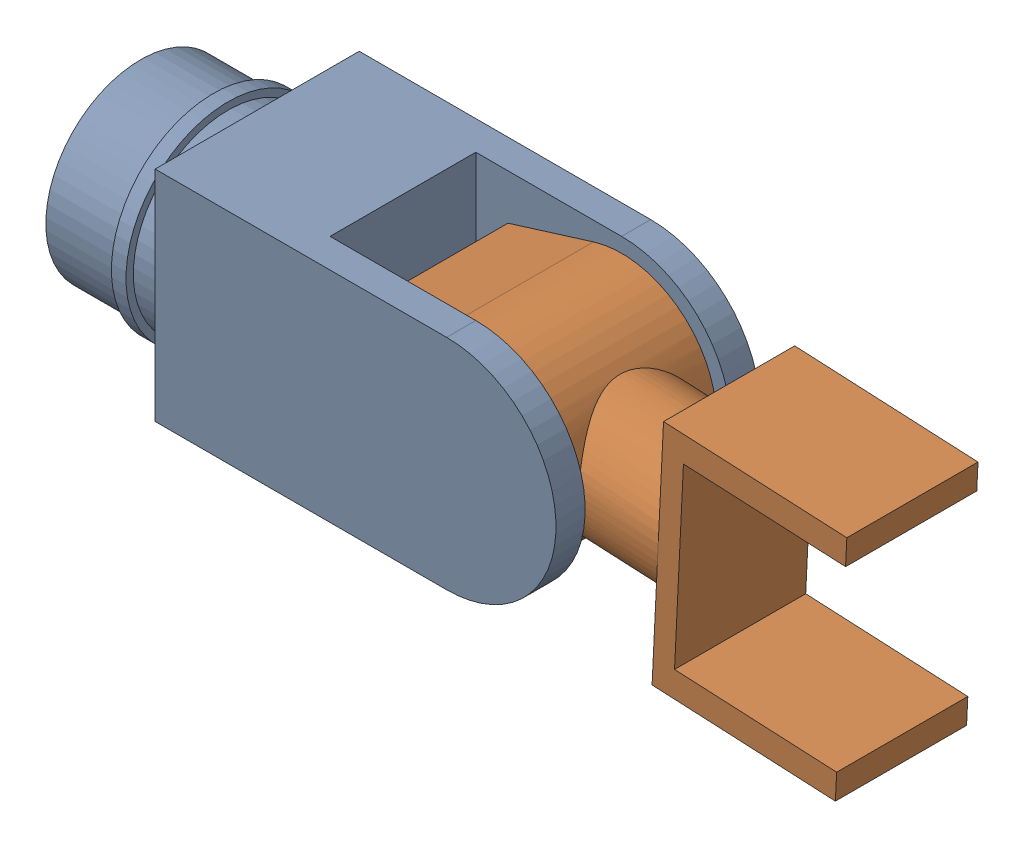
SolidWorks assembly BRAZO2, configuration Default. Lengths in mm.
Overall size (529.53 176.35 140).
2 component instances, 2 part files, 2 mates.
Components (placement in the parent):
- P2-1: P2 [Default] at (-431.7553 215.7042 295.9034) size (355 150 140)
- 5-1: 5 [Default] at (88.2447 215.7042 295.9034) x (0.998806 -0.048861 0) z (0 0 1) size (325.9 160.61 100)
Mates (geometry in assembly coordinates):
- Concentric1: concentric aligned: cylinder of P2-1 through (88.2447 215.7042 375.9054) axis (0 0 -1) radius 50; cylinder of 5-1 through (88.2447 215.7042 345.9034) axis (0 0 -1) radius 50
- Coincident1: coincident anti-aligned: plane of P2-1 through (88.2447 215.7042 245.9034) normal (0 0 1); plane of 5-1 through (88.2447 215.7042 245.9034) normal (0 0 -1)
